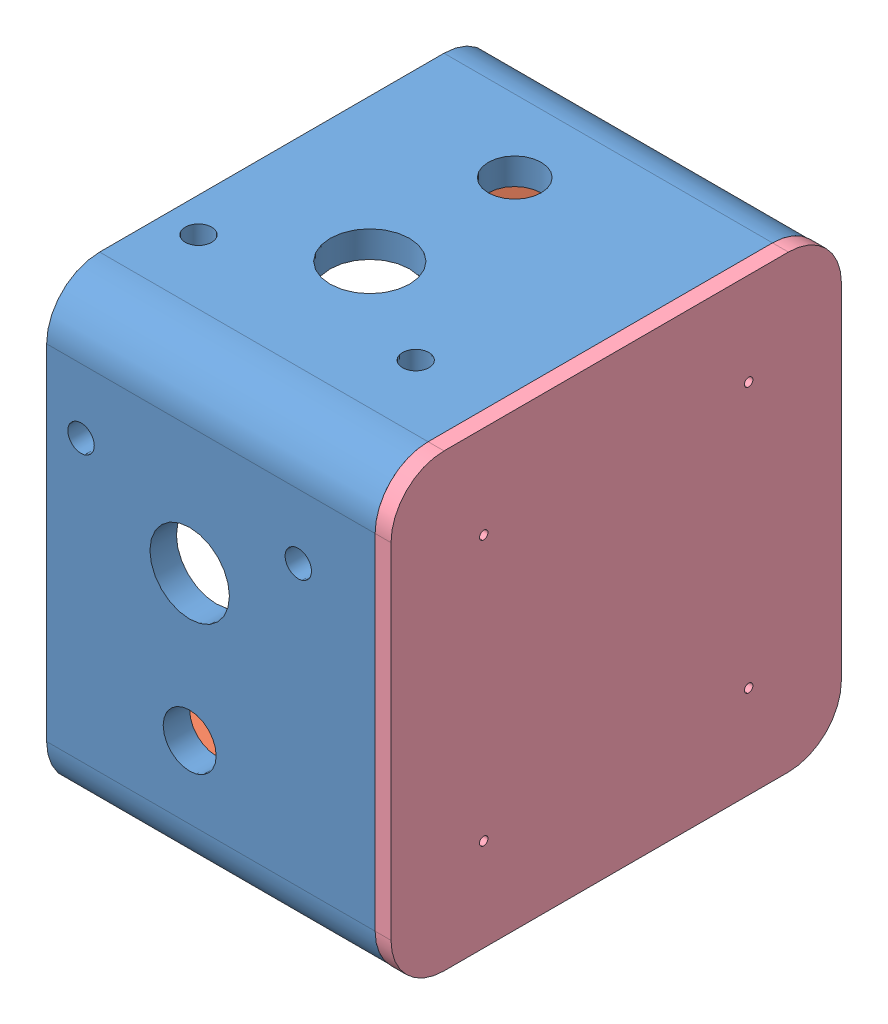
SolidWorks assembly station, configuration 默认. Lengths in mm.
Overall size (65 85 85).
16 component instances, 8 part files, 25 mates.
Components (placement in the parent):
- box-1: box [默认] at (22.3168 30.295 39.4744) size (62 85 85)
- motor_stator-1: motor_stator [默认] at (57.3168 -12.205 47.9744) x (0 0 1) z (-1 0 0) size (50.8 11.53 53.28)
- motor_rotor-1: motor_rotor [默认] at (57.3168 -0.705 47.9744) x (0.579228 0 0.815166) z (-0.815166 0 0.579228) size (33.9 11.85 33.9)
- motor_stator-2: motor_stator [默认] at (57.3168 38.795 -3.0256) x (0 1 0) z (1 0 0) size (50.8 11.53 53.28)
- motor_rotor-2: motor_rotor [默认] at (57.3168 38.795 8.4744) x (-0.999094 -0.042567 0) z (-0.042567 0.999094 0) size (33.9 11.85 33.9)
- back-1: back [默认] at (87.3168 30.295 39.4744) x (0 -1 0) z (0 0 1) size (85 8 85)
- axis2-1: axis2 [默认] at (80.2915 28.7829 22.9409) x (-0.462683 -0.886524 0) z (-0.886524 0.462683 0) size (25 16 25)
  - r3-1: r3 [默认] at (1.754 -7.3165 25) size (25 16 25)
  - m1-1: m1 [默认] at (1.754 2.7585 28.64) x (0 1 0) z (1 0 0) size (8 2 8)
  - mirror-1: mirror [默认] at (4.714 2.5835 24.54) x (0 0 -1) z (0 1 0) size (4.95 5 4.93)
- axis2-2: axis2 [默认] at (76.68 13.7615 32.0639) x (0.579228 0 0.815166) z (-0.815166 0 0.579228) size (25 16 25)
  - r3-1: r3 [默认] at (1.754 -7.3165 25) size (25 16 25)
  - m1-1: m1 [默认] at (1.754 2.7585 28.64) x (0 1 0) z (1 0 0) size (8 2 8)
  - mirror-1: mirror [默认] at (4.714 2.5835 24.54) x (0 0 -1) z (0 1 0) size (4.95 5 4.93)
- dianpian-1: dianpian [默认] at (57.3168 38.795 1.9744) x (0 -1 0) z (-1 0 0) size (50.8 4 53.28)
- dianpian-2: dianpian [默认] at (57.3162 -7.205 47.9741) x (0 0 -1) z (1 0 0) size (50.8 4 53.28)
Mates (geometry in assembly coordinates):
- 同心4: concentric aligned: cylinder of motor_stator-1 through (57.3168 -0.705 47.9744) axis (0 -1 0) radius 26.64; cylinder of motor_rotor-1 through (57.3168 6.445 47.9744) axis (0 -1 0) radius 12.49
- 同心10: concentric aligned: cylinder of box-1 through (36.8168 -17.205 59.8101) axis (0 1 0) radius 1.25; cylinder of motor_stator-1 through (36.8168 -11.205 59.8101) axis (0 1 0) radius 1.6
- 同心11: concentric anti-aligned: cylinder of box-1 through (57.3168 -17.205 47.9744) axis (0 1 0) radius 21.1; cylinder of motor_rotor-1 through (57.3168 6.445 47.9744) axis (0 -1 0) radius 12.49
- 重合14: coincident anti-aligned: plane of motor_stator-2 through (57.3168 38.795 7.4744) normal (0 0 1); plane of motor_rotor-2 through (57.3168 38.795 7.4744) normal (0 0 -1)
- 同心14: concentric aligned: cylinder of motor_stator-2 through (57.3168 38.795 8.4744) axis (0 0 -1) radius 26.64; cylinder of motor_rotor-2 through (57.3168 38.795 15.6244) axis (0 0 -1) radius 12.49
- 同心16: concentric aligned: cylinder of box-1 through (36.8168 50.6307 -8.0256) axis (0 0 1) radius 1.25; cylinder of motor_stator-2 through (36.8168 50.6307 -2.0256) axis (0 0 1) radius 1.6
- 重合16: coincident anti-aligned: plane of box-1 through (92.3168 30.295 39.4744) normal (1 0 0); plane of back-1 through (92.3168 30.295 39.4744) normal (-1 0 0)
- 重合17: coincident aligned: plane of box-1 through (92.3168 -12.205 -3.0256) normal (0 0 -1); plane of back-1 through (95.3168 72.795 -3.0256) normal (0 0 -1)
- 重合18: coincident aligned: plane of box-1 through (92.3168 -12.205 81.9744) normal (0 -1 0); plane of back-1 through (95.3168 -12.205 81.9744) normal (0 -1 0)
- 重合19: coincident anti-aligned: plane of motor_rotor-2 through (57.3168 38.795 15.6244) normal (0 0 1); plane of axis2-1/r3-1 through (57.3168 38.795 15.6244) normal (0 0 -1)
- 同心17: concentric aligned: cylinder of motor_rotor-2 through (57.3168 38.795 19.3244) axis (0 0 -1) radius 7.265; cylinder of axis2-1/r3-1 through (57.3168 38.795 31.6244) axis (0 0 -1) radius 7.3498
- 同心18: concentric aligned: cylinder of motor_rotor-2 through (62.175 48.1035 15.6244) axis (0 0 1) radius 0.8; cylinder of axis2-1/r3-1 through (62.175 48.1035 2.6244) axis (0 0 1) radius 1.15
- 重合20: coincident anti-aligned: plane of motor_rotor-1 through (57.3168 6.445 47.9744) normal (0 1 0); plane of axis2-2/r3-1 through (57.3168 6.445 47.9744) normal (0 -1 0)
- 同心19: concentric aligned: cylinder of motor_rotor-1 through (57.3168 10.145 47.9744) axis (0 -1 0) radius 7.265; cylinder of axis2-2/r3-1 through (57.3168 22.445 47.9744) axis (0 -1 0) radius 7.3498
- 同心20: concentric aligned: cylinder of motor_rotor-1 through (46.8634 6.445 48.9619) axis (0 1 0) radius 0.8; cylinder of axis2-2/r3-1 through (46.8634 -6.555 48.9619) axis (0 1 0) radius 1.15
- 同心21: concentric anti-aligned: cylinder of box-1 through (57.3168 38.795 -8.0256) axis (0 0 1) radius 21.1; cylinder of motor_stator-2 through (57.3168 38.795 2.2844) axis (0 0 -1) radius 18.64
- 重合21: coincident anti-aligned: plane of motor_stator-1 through (57.3168 -1.705 47.9744) normal (0 1 0); plane of motor_rotor-1 through (57.3168 -1.705 47.9744) normal (0 -1 0)
- 重合22: coincident anti-aligned: plane of box-1 through (92.3168 -7.205 1.9744) normal (0 0 1); plane of dianpian-1 through (57.3168 38.795 1.9744) normal (0 0 -1)
- 同心22: concentric aligned: cylinder of box-1 through (57.3168 38.795 -8.0256) axis (0 0 1) radius 21.1; cylinder of dianpian-1 through (57.3168 38.795 1.9744) axis (0 0 1) radius 21.25
- 同心23: concentric aligned: cylinder of box-1 through (77.8168 50.6307 -8.0256) axis (0 0 1) radius 1.25; cylinder of dianpian-1 through (77.8174 50.6311 1.9744) axis (0 0 1) radius 1.6
- 重合23: coincident anti-aligned: plane of motor_stator-2 through (57.3168 38.795 5.9744) normal (0 0 -1); plane of dianpian-1 through (57.3168 38.795 5.9744) normal (0 0 1)
- 重合24: coincident anti-aligned: plane of box-1 through (92.3168 -7.205 76.9744) normal (0 1 0); plane of dianpian-2 through (57.3162 -7.205 47.9741) normal (0 -1 0)
- 同心24: concentric anti-aligned: cylinder of motor_stator-1 through (57.3168 -6.895 47.9744) axis (0 -1 0) radius 18.64; cylinder of dianpian-2 through (57.3162 -7.205 47.9741) axis (0 1 0) radius 21.25
- 同心25: concentric aligned: cylinder of box-1 through (77.8168 -17.205 59.8101) axis (0 1 0) radius 1.25; cylinder of dianpian-2 through (77.8168 -7.205 59.8101) axis (0 1 0) radius 1.6
- 重合25: coincident anti-aligned: plane of motor_stator-1 through (57.3168 -3.205 47.9744) normal (0 -1 0); plane of dianpian-2 through (57.3162 -3.205 47.9741) normal (0 1 0)
